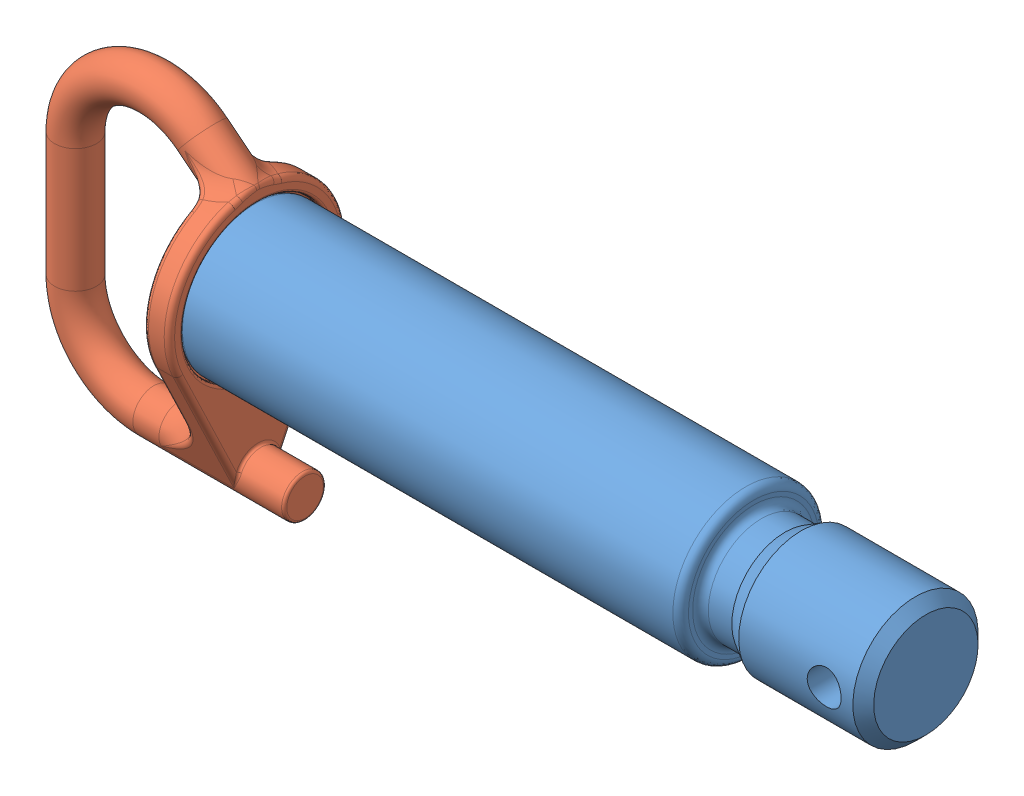
SolidWorks assembly 6304067, configuration Default. Lengths in mm.
Overall size (167 61.67 34).
4 component instances, 4 part files, 9 mates.
Components (placement in the parent):
- 6304068-1: 6304068 [Default] at origin size (129.5 28 28)
- 6304455-2: 6304455 [Default] at (-4 0 0) x (0 -1 0) z (0 0 -1) (suppressed, hidden)
- 6304454-1: 6304454 [Default] at (-5 0 0) x (0 0 -1) z (1 0 0) (suppressed, hidden)
- 15407-1: 15407 [Default] at (-3.5 0 0) x (0 0 -1) z (-1 0 0) size (34 61.67 48)
Mates (geometry in assembly coordinates):
- Concentric1: concentric: cylinder of 6304068-1 through (-12.9942 0 0) axis (-1 0 0) radius 14; cylinder of 6304454-1 through (0 0 0) axis (-1 0 0) radius 12.6
- Coincident6: coincident: plane of 6304068-1 through (0 13 0) normal (-1 0 0); plane of 15407-1 through (0 0 0) normal (1 0 0)
- Parallel1: parallel: plane of 6304454-1 through (-5 0 0) normal (0 0 -1); plane of assembly through (0 0 0) normal (0 0 1)
- Concentric3: concentric: cylinder of 6304068-1 through (-12.9942 0 0) axis (-1 0 0) radius 14; cylinder of 15407-1 through (1.5 0 0) axis (-1 0 0) radius 17
- Parallel2: parallel: plane of 15407-1; plane of assembly through (0 0 0) normal (0 0 1)
- Concentric4: concentric: cylinder of 6304455-2 through (-19 30 0) axis (1 0 0) radius 4; cylinder of 6304454-1 through (0 30 0) axis (-1 0 0) radius 4.1
- Coincident7: coincident: plane of 6304455-2 through (-4 0 0) normal (0 0 -1); plane of assembly through (0 0 0) normal (0 0 1)
- Coincident8: coincident: plane of 6304455-2 through (-5 -24 0) normal (1 0 0); plane of 6304454-1 through (-5 0 0) normal (-1 0 0)
- Coincident9: coincident: plane of 6304068-1 through (0 13 0) normal (-1 0 0); plane of 6304454-1 through (0 0 0) normal (1 0 0)
